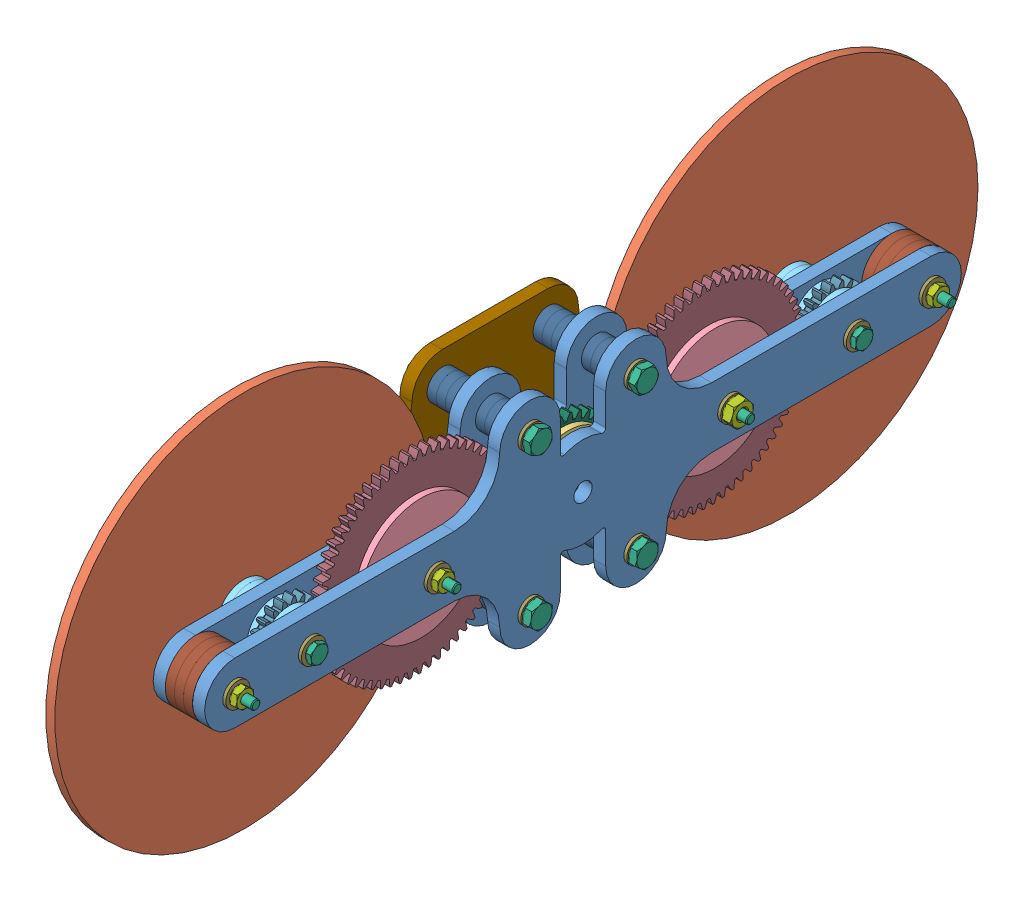
SolidWorks assembly ASSEMBLY LIM Mark 1, configuration Default. Lengths in mm.
Overall size (46 165.05 328.89).
104 component instances, 15 part files, 205 mates.
Components (placement in the parent):
- Frame_4mm-1: Frame_4mm [Default] at (139.7382 18.2666 142.7028) size (4 70 250)
- Wheel-1: Wheel [Default] at (118.7382 18.2666 232.7028) x (1 0 0) z (0 0.063899 0.997956) size (3 125 125)
- Wheel-2: Wheel [Default] at (118.7382 18.2666 52.7028) x (1 0 0) z (0 0.406893 0.913476) size (3 125 125)
- Frame_4mm-2: Frame_4mm [Default] at (126.7382 18.2666 142.7028) size (4 70 250)
- Spacer_driven_2mm-1: Spacer_driven_2mm [Default] at (131.7382 18.2666 142.7028) x (1 0 0) z (0 -0.019023 0.999819) size (2 30 30)
- Spacer_driven_2mm-2: Spacer_driven_2mm [Default] at (136.7382 18.2666 142.7028) x (1 0 0) z (0 0.007581 0.999971) size (2 30 30)
- Spacer_idler_2mm-1: Spacer_idler_2mm [Default] at (136.7382 18.2666 94.2028) x (1 0 0) z (0 0.85666 0.515882) size (2 40 40)
- Spacer_idler_2mm-3: Spacer_idler_2mm [Default] at (136.7382 18.2666 191.2028) x (1 0 0) z (0 0.00445 0.99999) size (2 40 40)
- Spacer_wheel_2mm-1: Spacer_wheel_2mm [Default] at (131.7382 18.2666 232.7028) size (2 18 18)
- Spacer_wheel_2mm-2: Spacer_wheel_2mm [Default] at (136.7382 18.2666 232.7028) x (1 0 0) z (0 0.141629 0.98992) size (2 18 18)
- Spacer_wheel_2mm-4: Spacer_wheel_2mm [Default] at (131.7382 18.2666 52.7028) size (2 18 18)
- hex bolt gradeab_iso-2: hex bolt gradeab_iso [ISO 4014 - M3 x 30 x 12-N] at (146.7382 18.2666 52.7028) x (-1 0 0) z (0 0.901352 0.433087) size (32 6.35 5.5)
- hex bolt gradeab_iso-3: hex bolt gradeab_iso [ISO 4014 - M3 x 30 x 12-N] at (146.7382 18.2666 232.7028) x (-1 0 0) z (0 0.928498 -0.371338) size (32 6.35 5.5)
- hex bolt gradeab_iso-4: hex bolt gradeab_iso [ISO 4014 - M3 x 25 x 12-N] at (123.7382 18.2666 94.2028) x (1 0 0) z (0 0.001655 0.999999) size (27 6.35 5.5)
- hex bolt gradeab_iso-5: hex bolt gradeab_iso [ISO 4014 - M3 x 25 x 12-N] at (123.7382 18.2666 191.2028) x (1 0 0) z (0 -0.941624 0.336667) size (27 6.35 5.5)
- hex bolt gradeab_iso-6: hex bolt gradeab_iso [ISO 4014 - M3 x 25 x 12-N] at (123.7382 18.2666 257.7028) x (1 0 0) z (0 0.542297 0.840187) size (27 6.35 5.5)
- hex bolt gradeab_iso-8: hex bolt gradeab_iso [ISO 4014 - M3 x 25 x 12-N] at (123.7382 18.2666 27.7028) x (1 0 0) z (0 -0.023682 0.99972) size (27 6.35 5.5)
- hex nut style 1 gradeab_iso-3: hex nut style 1 gradeab_iso [ISO - 4032 - M3 - W - N] at (139.1382 18.2666 52.7028) x (0 0.924225 0.381849) z (1 0 0) size (5.5 6.35 2.4)
- hex nut style 1 gradeab_iso-4: hex nut style 1 gradeab_iso [ISO - 4032 - M3 - W - N] at (131.3382 18.2666 52.7028) x (0 0 1) z (-1 0 0) size (5.5 6.35 2.4)
- hex nut style 1 gradeab_iso-5: hex nut style 1 gradeab_iso [ISO - 4032 - M3 - W - N] at (124.1382 18.2666 52.7028) x (0 0.924225 0.381849) z (1 0 0) size (5.5 6.35 2.4)
- hex nut style 1 gradeab_iso-6: hex nut style 1 gradeab_iso [ISO - 4032 - M3 - W - N] at (139.1382 18.2666 232.7028) x (0 -0.924225 -0.381849) z (1 0 0) size (5.5 6.35 2.4)
- hex nut style 1 gradeab_iso-7: hex nut style 1 gradeab_iso [ISO - 4032 - M3 - W - N] at (124.1382 18.2666 232.7028) x (0 0 -1) z (1 0 0) size (5.5 6.35 2.4)
- hex nut style 1 gradeab_iso-11: hex nut style 1 gradeab_iso [ISO - 4032 - M3 - W - N] at (147.1382 18.2666 257.7028) x (0 -0.181908 -0.983316) z (1 0 0) size (5.5 6.35 2.4)
- hex nut style 1 gradeab_iso-13: hex nut style 1 gradeab_iso [ISO - 4032 - M3 - W - N] at (131.3382 18.2666 232.7028) x (0 0 1) z (-1 0 0) size (5.5 6.35 2.4)
- hex nut style 1 gradeab_iso-14: hex nut style 1 gradeab_iso [ISO - 4032 - M3 - W - N] at (116.3382 18.2666 232.7028) x (0 -0.924225 -0.381849) z (-1 0 0) size (5.5 6.35 2.4)
- hex nut style 1 gradeab_iso-15: hex nut style 1 gradeab_iso [ISO - 4032 - M3 - W - N] at (147.1382 18.2666 27.7028) x (0 0.064847 -0.997895) z (1 0 0) size (5.5 6.35 2.4)
- Spacer_idler_circle_2mm-1: Spacer_idler_circle_2mm [Default] at (131.7382 18.2666 191.2028) size (2 40 40)
- Spacer_idler_circle_2mm-2: Spacer_idler_circle_2mm [Default] at (131.7382 18.2666 94.2028) x (1 0 0) z (0 0.14655 0.989203) size (2 40 40)
- Frame_outer_4mm_revised-1: Frame_outer_4mm_revised [Default] at (110.7382 18.2666 142.7028) size (4 70 200)
- hex bolt gradeab_iso-9: hex bolt gradeab_iso [ISO 4014 - M4 x 40 x 14-N] at (147.5382 43.2666 125.2028) x (-1 0 0) z (0 0.591668 0.806182) size (42.8 8.08 7)
- hex bolt gradeab_iso-10: hex bolt gradeab_iso [ISO 4014 - M4 x 40 x 14-N] at (147.5382 -6.7334 125.2028) x (-1 0 0) z (0 -0.935172 -0.354194) size (42.8 8.08 7)
- hex bolt gradeab_iso-11: hex bolt gradeab_iso [ISO 4014 - M4 x 40 x 14-N] at (147.5382 43.2666 160.2028) x (-1 0 0) z (0 -0.143736 0.989616) size (42.8 8.08 7)
- hex bolt gradeab_iso-12: hex bolt gradeab_iso [ISO 4014 - M4 x 40 x 14-N] at (147.5382 -6.7334 160.2028) x (-1 0 0) z (0 -0.737321 0.675543) size (42.8 8.08 7)
- hex nut style 1 gradeab_iso-18: hex nut style 1 gradeab_iso [ISO - 4032 - M4 - W - N] at (106.5382 43.2666 160.2028) x (0 0.358577 0.9335) z (-1 0 0) size (7 8.08 3.2)
- hex nut style 1 gradeab_iso-19: hex nut style 1 gradeab_iso [ISO - 4032 - M4 - W - N] at (106.5382 -6.7334 160.2028) x (0 -0.052351 0.998629) z (-1 0 0) size (7 8.08 3.2)
- hex nut style 1 gradeab_iso-20: hex nut style 1 gradeab_iso [ISO - 4032 - M4 - W - N] at (106.5382 43.2666 125.2028) x (0 0.360849 0.932624) z (-1 0 0) size (7 8.08 3.2)
- hex nut style 1 gradeab_iso-21: hex nut style 1 gradeab_iso [ISO - 4032 - M4 - W - N] at (147.9382 18.2666 94.2028) x (0 -0.986828 -0.161771) z (1 0 0) size (7 8.08 3.2)
- hex nut style 1 gradeab_iso-22: hex nut style 1 gradeab_iso [ISO - 4032 - M3 - W - N] at (116.3382 18.2666 52.7028) x (0 0.924225 0.381849) z (-1 0 0) size (5.5 6.35 2.4)
- hex nut style 1 gradeab_iso-24: hex nut style 1 gradeab_iso [ISO - 4032 - M3 - W - N] at (147.1382 18.2666 191.2028) x (0 0 -1) z (1 0 0) size (5.5 6.35 2.4)
- Spacer_support_inner_3mm-5: Spacer_support_inner_3mm [Default] at (133.7382 43.2666 160.2028) x (-1 0 0) z (0 0.924225 0.381849) size (3 10 10)
- Spacer_support_inner_3mm-6: Spacer_support_inner_3mm [Default] at (139.7382 43.2666 160.2028) x (-1 0 0) z (0 0.924225 0.381849) size (3 10 10)
- Spacer_support_inner_3mm-7: Spacer_support_inner_3mm [Default] at (136.7382 43.2666 125.2028) x (-1 0 0) z (0 0.924225 0.381849) size (3 10 10)
- Spacer_support_inner_3mm-8: Spacer_support_inner_3mm [Default] at (133.7382 43.2666 125.2028) x (-1 0 0) z (0 0.924225 0.381849) size (3 10 10)
- Spacer_support_inner_3mm-9: Spacer_support_inner_3mm [Default] at (139.7382 -6.7334 125.2028) x (-1 0 0) z (0 0.924225 0.381849) size (3 10 10)
- Spacer_support_inner_3mm-10: Spacer_support_inner_3mm [Default] at (136.7382 43.2666 160.2028) x (-1 0 0) z (0 0.924225 0.381849) size (3 10 10)
- Spacer_support_inner_3mm-11: Spacer_support_inner_3mm [Default] at (136.7382 43.2666 125.2028) size (3 10 10)
- Spacer_support_outer_3mm-8: Spacer_support_outer_3mm [Default] at (133.7382 18.2666 27.7028) size (3 20 20)
- Spacer_support_outer_3mm-9: Spacer_support_outer_3mm [Default] at (136.7382 18.2666 27.7028) size (3 20 20)
- Spacer_support_outer_3mm-10: Spacer_support_outer_3mm [Default] at (130.7382 18.2666 27.7028) size (3 20 20)
- Spacer_support_outer_3mm-12: Spacer_support_outer_3mm [Default] at (139.7382 18.2666 257.7028) x (-1 0 0) z (0 0.924225 0.381849) size (3 20 20)
- Spacer_support_outer_3mm-13: Spacer_support_outer_3mm [Default] at (130.7382 18.2666 257.7028) size (3 20 20)
- Spacer_support_outer_3mm-16: Spacer_support_outer_3mm [Default] at (133.7382 18.2666 257.7028) size (3 20 20)
- plain washer 10669 type nl_iso-1: plain washer 10669 type nl_iso [ISO 10669-3-N] at (143.7382 43.2666 125.2028) size (1 8 8)
- plain washer 10669 type nl_iso-2: plain washer 10669 type nl_iso [ISO 10669-3-N] at (144.7382 18.2666 257.7028) x (-1 0 0) z (0 0.924225 0.381849) size (1 8 8)
- plain washer 10669 type nl_iso-3: plain washer 10669 type nl_iso [ISO 10669-3-N] at (144.7382 18.2666 232.7028) x (-1 0 0) z (0 0.924225 0.381849) size (1 8 8)
- plain washer 10669 type nl_iso-4: plain washer 10669 type nl_iso [ISO 10669-3-N] at (144.7382 18.2666 191.2028) x (-1 0 0) z (0 0.924225 0.381849) size (1 8 8)
- plain washer 10669 type nl_iso-5: plain washer 10669 type nl_iso [ISO 10669-3-N] at (144.7382 18.2666 94.2028) x (-1 0 0) z (0 0.939531 0.342464) size (1 8 8)
- plain washer 10669 type nl_iso-6: plain washer 10669 type nl_iso [ISO 10669-3-N] at (126.7382 18.2666 191.2028) x (-1 0 0) z (0 0.355388 0.934719) size (1 8 8)
- plain washer 10669 type nl_iso-7: plain washer 10669 type nl_iso [ISO 10669-3-N] at (125.7382 18.2666 257.7028) size (1 8 8)
- plain washer 10669 type nl_iso-8: plain washer 10669 type nl_iso [ISO 10669-3-N] at (125.7382 18.2666 27.7028) x (1 0 0) z (0 -0.53185 0.846839) size (1 8 8)
- plain washer 10669 type nl_iso-10: plain washer 10669 type nl_iso [ISO 10669-3-N] at (110.7382 -6.7334 160.2028) x (-1 0 0) z (0 -0.924225 -0.381849) size (1 8 8)
- plain washer 10669 type nl_iso-11: plain washer 10669 type nl_iso [ISO 10669-3-N] at (110.7382 43.2666 125.2028) x (-1 0 0) z (0 0.924225 0.381849) size (1 8 8)
- plain washer 10669 type nl_iso-12: plain washer 10669 type nl_iso [ISO 10669-3-N] at (110.7382 43.2666 160.2028) x (-1 0 0) z (0 0.924225 0.381849) size (1 8 8)
- plain washer 10669 type nl_iso-13: plain washer 10669 type nl_iso [ISO 10669-3-N] at (110.7382 -6.7334 125.2028) x (-1 0 0) z (0 0.924225 0.381849) size (1 8 8)
- plain washer 10669 type nl_iso-15: plain washer 10669 type nl_iso [ISO 10669-3-N] at (144.7382 43.2666 160.2028) x (-1 0 0) z (0 0.924225 0.381849) size (1 8 8)
- plain washer 10669 type nl_iso-16: plain washer 10669 type nl_iso [ISO 10669-3-N] at (144.7382 18.2666 27.7028) x (-1 0 0) z (0 0.924225 0.381849) size (1 8 8)
- plain washer 10669 type nl_iso-17: plain washer 10669 type nl_iso [ISO 10669-3-N] at (126.7382 18.2666 94.2028) x (-1 0 0) z (0 -0.924225 -0.381849) size (1 8 8)
- plain washer 10669 type nl_iso-18: plain washer 10669 type nl_iso [ISO 10669-3-N] at (143.7382 -6.7334 125.2028) size (1 8 8)
- plain washer 10669 type nl_iso-19: plain washer 10669 type nl_iso [ISO 10669-3-N] at (144.7382 -6.7334 160.2028) x (-1 0 0) z (0 0.924225 0.381849) size (1 8 8)
- plain washer 10669 type nl_iso-20: plain washer 10669 type nl_iso [ISO 10669-3-N] at (144.7382 18.2666 52.7028) x (-1 0 0) z (0 0.924225 0.381849) size (1 8 8)
- Spacer_support_inner_3mm-14: Spacer_support_inner_3mm [Default] at (133.7382 -6.7334 160.2028) size (3 10 10)
- Spacer_support_inner_3mm-17: Spacer_support_inner_3mm [Default] at (130.7382 -6.7334 160.2028) size (3 10 10)
- Spacer_support_inner_3mm-18: Spacer_support_inner_3mm [Default] at (136.7382 -6.7334 160.2028) size (3 10 10)
- Spacer_support_inner_3mm-19: Spacer_support_inner_3mm [Default] at (130.7382 -6.7334 125.2028) size (3 10 10)
- Spacer_support_inner_3mm-20: Spacer_support_inner_3mm [Default] at (133.7382 -6.7334 125.2028) size (3 10 10)
- Spacer_support_inner_3mm-21: Spacer_support_inner_3mm [Default] at (117.7382 43.2666 125.2028) size (3 10 10)
- Spacer_support_inner_3mm-22: Spacer_support_inner_3mm [Default] at (126.7382 43.2666 125.2028) x (-1 0 0) z (0 0.924225 0.381849) size (3 10 10)
- Spacer_support_inner_3mm-23: Spacer_support_inner_3mm [Default] at (120.7382 43.2666 125.2028) size (3 10 10)
- Spacer_support_inner_3mm-24: Spacer_support_inner_3mm [Default] at (120.7382 -6.7334 160.2028) size (3 10 10)
- Spacer_support_inner_3mm-25: Spacer_support_inner_3mm [Default] at (126.7382 -6.7334 160.2028) x (-1 0 0) z (0 0.924225 0.381849) size (3 10 10)
- Spacer_support_inner_3mm-26: Spacer_support_inner_3mm [Default] at (117.7382 -6.7334 160.2028) size (3 10 10)
- Spacer_support_inner_3mm-27: Spacer_support_inner_3mm [Default] at (120.7382 43.2666 160.2028) size (3 10 10)
- Spacer_support_inner_3mm-28: Spacer_support_inner_3mm [Default] at (126.7382 43.2666 160.2028) x (-1 0 0) z (0 0.924225 0.381849) size (3 10 10)
- Spacer_support_inner_3mm-29: Spacer_support_inner_3mm [Default] at (117.7382 43.2666 160.2028) size (3 10 10)
- Spacer_support_inner_3mm-30: Spacer_support_inner_3mm [Default] at (120.7382 -6.7334 125.2028) size (3 10 10)
- Spacer_support_inner_3mm-31: Spacer_support_inner_3mm [Default] at (126.7382 -6.7334 125.2028) x (-1 0 0) z (0 0.924225 0.381849) size (3 10 10)
- Spacer_support_inner_3mm-32: Spacer_support_inner_3mm [Default] at (117.7382 -6.7334 125.2028) size (3 10 10)
- Spacer_wheel_2mm-10: Spacer_wheel_2mm [Default] at (123.7382 18.2666 52.7028) x (1 0 0) z (0 -0.924225 -0.381849) size (2 18 18)
- Spacer_wheel_2mm-11: Spacer_wheel_2mm [Default] at (123.7382 18.2666 52.7028) x (-1 0 0) z (0 -0.131421 -0.991327) size (2 18 18)
- Spacer_wheel_2mm-14: Spacer_wheel_2mm [Default] at (123.7382 18.2666 232.7028) x (-1 0 0) z (0 -0.866025 0.5) size (2 18 18)
- Spacer_wheel_2mm-15: Spacer_wheel_2mm [Default] at (123.7382 18.2666 232.7028) size (2 18 18)
- Spacer_support_inner_3mm-33: Spacer_support_inner_3mm [Default] at (117.7382 43.2666 125.2028) x (-1 0 0) z (0 0.924225 0.381849) size (3 10 10)
- Spacer_support_inner_3mm-34: Spacer_support_inner_3mm [Default] at (117.7382 -6.7334 125.2028) x (-1 0 0) z (0 0.924225 0.381849) size (3 10 10)
- Spacer_support_inner_3mm-35: Spacer_support_inner_3mm [Default] at (117.7382 -6.7334 160.2028) x (-1 0 0) z (0 0.924225 0.381849) size (3 10 10)
- Spacer_support_inner_3mm-36: Spacer_support_inner_3mm [Default] at (117.7382 43.2666 160.2028) x (-1 0 0) z (0 0.924225 0.381849) size (3 10 10)
- Spacer_support_outer_3mm-20: Spacer_support_outer_3mm [Default] at (115.7382 18.2666 52.7028) size (3 20 20)
- Spacer_support_outer_3mm-21: Spacer_support_outer_3mm [Default] at (115.7382 18.2666 232.7028) size (3 20 20)
- hex nut style 1 gradeab_iso-25: hex nut style 1 gradeab_iso [ISO - 4032 - M4 - W - N] at (106.5382 -6.7334 125.2028) x (0 -0.052351 0.998629) z (-1 0 0) size (7 8.08 3.2)
- Spacer_wheel_2mm-16: Spacer_wheel_2mm [Default] at (136.7382 18.2666 52.7028) x (1 0 0) z (0 0.141629 0.98992) size (2 18 18)
- Gear_idler_3mm-3: Gear_idler_3mm [ISO - Spur gear 1M 62T 20PA 3FW ---S62A75H50L3.0N] at (133.7382 18.2666 191.2028) size (3 63.95 64)
- Gear_idler_3mm-4: Gear_idler_3mm [ISO - Spur gear 1M 62T 20PA 3FW ---S62A75H50L3.0N] at (133.7382 18.2666 94.2028) size (3 63.95 64)
- Gear_slave_3mm-3: Gear_slave_3mm [ISO - Spur gear 1M 20T 20PA 3FW ---S20A75H50L3.0N] at (133.7382 18.2666 232.7028) size (3 21.8 21.8)
- Gear_slave_3mm-4: Gear_slave_3mm [ISO - Spur gear 1M 20T 20PA 3FW ---S20A75H50L3.0N] at (133.7382 18.2666 52.7028) x (1 0 0) z (0 0.10181 0.994804) size (3 21.8 21.8)
- Gear_master_3mm-2: Gear_master_3mm [ISO - Spur gear 1M 34T 20PA 3FW ---S34A75H50L3.0N] at (133.7382 18.2666 142.7028) x (1 0 0) z (0 -0.290928 0.956745) size (3 35.9 36)
Mates (geometry in assembly coordinates):
- Distance1: distance = 1 mm anti-aligned: plane of Frame_4mm-1 through (139.7382 18.2666 142.7028) normal (-1 0 0); plane of Spacer_driven_2mm-2 through (138.7382 18.2666 142.7028) normal (1 0 0)
- Coincident326: coincident aligned: axis of Frame_4mm-1 through (139.7382 43.2666 125.2028) axis (1 0 0); axis of hex bolt gradeab_iso-9 through (105.1282 43.2666 125.2028) axis (1 0 0)
- Coincident330: coincident anti-aligned: axis of hex bolt gradeab_iso-9 through (105.1282 43.2666 125.2028) axis (1 0 0); axis of plain washer 10669 type nl_iso-1 through (144.7382 43.2666 125.2028) axis (-1 0 0)
- Coincident331: coincident anti-aligned: plane of hex bolt gradeab_iso-9 through (144.7382 40.0085 127.594) normal (-1 0 0); plane of plain washer 10669 type nl_iso-1 through (144.7382 43.2666 125.2028) normal (1 0 0)
- Coincident332: coincident anti-aligned: plane of Frame_4mm-1 through (143.7382 18.2666 142.7028) normal (1 0 0); plane of plain washer 10669 type nl_iso-1 through (143.7382 43.2666 125.2028) normal (-1 0 0)
- Coincident335: coincident aligned: axis of Frame_4mm-1 through (139.7382 18.2666 257.7028) axis (1 0 0); axis of plain washer 10669 type nl_iso-2 through (143.7382 18.2666 257.7028) axis (1 0 0)
- Coincident336: coincident anti-aligned: plane of Frame_4mm-1 through (143.7382 18.2666 142.7028) normal (1 0 0); plane of plain washer 10669 type nl_iso-2 through (143.7382 18.2666 257.7028) normal (-1 0 0)
- Coincident337: coincident anti-aligned: axis of Frame_4mm-1 through (139.7382 -6.7334 125.2028) axis (1 0 0); axis of plain washer 10669 type nl_iso-18 through (144.7382 -6.7334 125.2028) axis (-1 0 0)
- Coincident338: coincident anti-aligned: plane of Frame_4mm-1 through (143.7382 18.2666 142.7028) normal (1 0 0); plane of plain washer 10669 type nl_iso-18 through (143.7382 -6.7334 125.2028) normal (-1 0 0)
- Coincident339: coincident aligned: axis of Frame_4mm-1 through (139.7382 -6.7334 160.2028) axis (1 0 0); axis of plain washer 10669 type nl_iso-19 through (143.7382 -6.7334 160.2028) axis (1 0 0)
- Coincident340: coincident anti-aligned: plane of Frame_4mm-1 through (143.7382 18.2666 142.7028) normal (1 0 0); plane of plain washer 10669 type nl_iso-19 through (143.7382 -6.7334 160.2028) normal (-1 0 0)
- Coincident341: coincident aligned: axis of Frame_4mm-1 through (139.7382 43.2666 160.2028) axis (1 0 0); axis of plain washer 10669 type nl_iso-15 through (143.7382 43.2666 160.2028) axis (1 0 0)
- Coincident342: coincident anti-aligned: plane of Frame_4mm-1 through (143.7382 18.2666 142.7028) normal (1 0 0); plane of plain washer 10669 type nl_iso-15 through (143.7382 43.2666 160.2028) normal (-1 0 0)
- Coincident343: coincident aligned: axis of Frame_4mm-1 through (139.7382 18.2666 232.7028) axis (1 0 0); axis of plain washer 10669 type nl_iso-3 through (143.7382 18.2666 232.7028) axis (1 0 0)
- Coincident344: coincident anti-aligned: plane of Frame_4mm-1 through (143.7382 18.2666 142.7028) normal (1 0 0); plane of plain washer 10669 type nl_iso-3 through (143.7382 18.2666 232.7028) normal (-1 0 0)
- Coincident347: coincident aligned: axis of Frame_4mm-1 through (139.7382 18.2666 191.2028) axis (1 0 0); axis of plain washer 10669 type nl_iso-4 through (143.7382 18.2666 191.2028) axis (1 0 0)
- Coincident348: coincident anti-aligned: plane of Frame_4mm-1 through (143.7382 18.2666 142.7028) normal (1 0 0); plane of plain washer 10669 type nl_iso-4 through (143.7382 18.2666 191.2028) normal (-1 0 0)
- Coincident349: coincident aligned: axis of Frame_4mm-1 through (139.7382 18.2666 94.2028) axis (1 0 0); axis of plain washer 10669 type nl_iso-5 through (143.7382 18.2666 94.2028) axis (1 0 0)
- Coincident350: coincident anti-aligned: plane of Frame_4mm-1 through (143.7382 18.2666 142.7028) normal (1 0 0); plane of plain washer 10669 type nl_iso-5 through (143.7382 18.2666 94.2028) normal (-1 0 0)
- Coincident351: coincident aligned: axis of Frame_4mm-1 through (139.7382 18.2666 52.7028) axis (1 0 0); axis of plain washer 10669 type nl_iso-20 through (143.7382 18.2666 52.7028) axis (1 0 0)
- Coincident352: coincident anti-aligned: plane of Frame_4mm-1 through (143.7382 18.2666 142.7028) normal (1 0 0); plane of plain washer 10669 type nl_iso-20 through (143.7382 18.2666 52.7028) normal (-1 0 0)
- Coincident353: coincident aligned: axis of Frame_4mm-1 through (139.7382 18.2666 27.7028) axis (1 0 0); axis of plain washer 10669 type nl_iso-16 through (143.7382 18.2666 27.7028) axis (1 0 0)
- Coincident354: coincident anti-aligned: plane of Frame_4mm-1 through (143.7382 18.2666 142.7028) normal (1 0 0); plane of plain washer 10669 type nl_iso-16 through (143.7382 18.2666 27.7028) normal (-1 0 0)
- Coincident355: coincident aligned: axis of hex bolt gradeab_iso-2 through (115.0187 18.2666 52.7028) axis (1 0 0); axis of plain washer 10669 type nl_iso-20 through (143.7382 18.2666 52.7028) axis (1 0 0)
- Coincident356: coincident anti-aligned: plane of hex bolt gradeab_iso-2 through (144.7382 16.8914 55.5649) normal (-1 0 0); plane of plain washer 10669 type nl_iso-20 through (144.7382 18.2666 52.7028) normal (1 0 0)
- Concentric3: concentric aligned: axis of hex bolt gradeab_iso-10 through (146.799 -6.7334 125.2028) axis (1 0 0); circle of plain washer 10669 type nl_iso-18
- Coincident357: coincident aligned: axis of Frame_4mm-1 through (139.7382 43.2666 160.2028) axis (1 0 0); axis of hex bolt gradeab_iso-11 through (105.1282 43.2666 160.2028) axis (1 0 0)
- Coincident358: coincident anti-aligned: plane of hex bolt gradeab_iso-11 through (144.7382 39.2671 159.6219) normal (-1 0 0); plane of plain washer 10669 type nl_iso-15 through (144.7382 43.2666 160.2028) normal (1 0 0)
- Coincident359: coincident anti-aligned: plane of hex bolt gradeab_iso-10 through (144.7382 -5.3019 121.4233) normal (-1 0 0); plane of plain washer 10669 type nl_iso-18 through (144.7382 -6.7334 125.2028) normal (1 0 0)
- Coincident360: coincident aligned: axis of hex bolt gradeab_iso-12 through (105.1282 -6.7334 160.2028) axis (1 0 0); axis of plain washer 10669 type nl_iso-19 through (143.7382 -6.7334 160.2028) axis (1 0 0)
- Coincident361: coincident anti-aligned: plane of hex bolt gradeab_iso-12 through (144.7382 -9.4636 157.2229) normal (-1 0 0); plane of plain washer 10669 type nl_iso-19 through (144.7382 -6.7334 160.2028) normal (1 0 0)
- Coincident362: coincident aligned: axis of Frame_4mm-1 through (139.7382 18.2666 232.7028) axis (1 0 0); axis of hex bolt gradeab_iso-3 through (146.1574 18.2666 232.7028) axis (1 0 0)
- Coincident363: coincident anti-aligned: plane of hex bolt gradeab_iso-3 through (144.7382 19.4458 235.6511) normal (-1 0 0); plane of plain washer 10669 type nl_iso-3 through (144.7382 18.2666 232.7028) normal (1 0 0)
- Coincident364: coincident aligned: axis of hex bolt gradeab_iso-11 through (105.1282 43.2666 160.2028) axis (1 0 0); axis of Spacer_support_inner_3mm-6 through (136.7382 43.2666 160.2028) axis (1 0 0)
- Coincident365: coincident anti-aligned: plane of Frame_4mm-1 through (139.7382 18.2666 142.7028) normal (-1 0 0); plane of Spacer_support_inner_3mm-6 through (139.7382 43.2666 160.2028) normal (1 0 0)
- Coincident366: coincident aligned: axis of hex bolt gradeab_iso-11 through (105.1282 43.2666 160.2028) axis (1 0 0); axis of Spacer_support_inner_3mm-10 through (133.7382 43.2666 160.2028) axis (1 0 0)
- Coincident367: coincident anti-aligned: plane of Spacer_support_inner_3mm-6 through (136.7382 43.2666 160.2028) normal (-1 0 0); plane of Spacer_support_inner_3mm-10 through (136.7382 43.2666 160.2028) normal (1 0 0)
- Coincident368: coincident aligned: axis of hex bolt gradeab_iso-11 through (105.1282 43.2666 160.2028) axis (1 0 0); axis of Spacer_support_inner_3mm-5 through (130.7382 43.2666 160.2028) axis (1 0 0)
- Coincident369: coincident anti-aligned: plane of Spacer_support_inner_3mm-5 through (133.7382 43.2666 160.2028) normal (1 0 0); plane of Spacer_support_inner_3mm-10 through (133.7382 43.2666 160.2028) normal (-1 0 0)
- Coincident370: coincident aligned: axis of hex bolt gradeab_iso-9 through (105.1282 43.2666 125.2028) axis (1 0 0); axis of Spacer_support_inner_3mm-7 through (133.7382 43.2666 125.2028) axis (1 0 0)
- Coincident371: coincident anti-aligned: axis of hex bolt gradeab_iso-9 through (105.1282 43.2666 125.2028) axis (1 0 0); axis of Spacer_support_inner_3mm-11 through (139.7382 43.2666 125.2028) axis (-1 0 0)
- Coincident372: coincident anti-aligned: plane of Frame_4mm-1 through (139.7382 18.2666 142.7028) normal (-1 0 0); plane of Spacer_support_inner_3mm-11 through (139.7382 43.2666 125.2028) normal (1 0 0)
- Coincident373: coincident anti-aligned: plane of Spacer_support_inner_3mm-7 through (136.7382 43.2666 125.2028) normal (1 0 0); plane of Spacer_support_inner_3mm-11 through (136.7382 43.2666 125.2028) normal (-1 0 0)
- Coincident374: coincident aligned: axis of hex bolt gradeab_iso-9 through (105.1282 43.2666 125.2028) axis (1 0 0); axis of Spacer_support_inner_3mm-8 through (130.7382 43.2666 125.2028) axis (1 0 0)
- Coincident375: coincident anti-aligned: plane of Spacer_support_inner_3mm-7 through (133.7382 43.2666 125.2028) normal (-1 0 0); plane of Spacer_support_inner_3mm-8 through (133.7382 43.2666 125.2028) normal (1 0 0)
- Coincident376: coincident aligned: axis of hex nut style 1 gradeab_iso-15 through (144.9387 18.2666 27.7028) axis (1 0 0); axis of plain washer 10669 type nl_iso-16 through (143.7382 18.2666 27.7028) axis (1 0 0)
- Coincident377: coincident anti-aligned: plane of hex nut style 1 gradeab_iso-15 through (144.7382 21.4353 27.9087) normal (-1 0 0); plane of plain washer 10669 type nl_iso-16 through (144.7382 18.2666 27.7028) normal (1 0 0)
- Coincident380: coincident aligned: axis of hex nut style 1 gradeab_iso-21 through (145.0087 18.2666 94.2028) axis (1 0 0); axis of plain washer 10669 type nl_iso-5 through (143.7382 18.2666 94.2028) axis (1 0 0)
- Coincident381: coincident aligned: axis of hex nut style 1 gradeab_iso-24 through (144.9387 18.2666 191.2028) axis (1 0 0); axis of plain washer 10669 type nl_iso-4 through (143.7382 18.2666 191.2028) axis (1 0 0)
- Coincident382: coincident anti-aligned: plane of hex nut style 1 gradeab_iso-24 through (144.7382 21.442 191.2028) normal (-1 0 0); plane of plain washer 10669 type nl_iso-4 through (144.7382 18.2666 191.2028) normal (1 0 0)
- Coincident383: coincident aligned: axis of hex nut style 1 gradeab_iso-11 through (144.9387 18.2666 257.7028) axis (1 0 0); axis of plain washer 10669 type nl_iso-2 through (143.7382 18.2666 257.7028) axis (1 0 0)
- Coincident384: coincident anti-aligned: plane of hex nut style 1 gradeab_iso-11 through (144.7382 21.389 257.1251) normal (-1 0 0); plane of plain washer 10669 type nl_iso-2 through (144.7382 18.2666 257.7028) normal (1 0 0)
- Coincident385: coincident anti-aligned: plane of Frame_4mm-1 through (139.7382 18.2666 142.7028) normal (-1 0 0); plane of Spacer_support_outer_3mm-12 through (139.7382 18.2666 257.7028) normal (1 0 0)
- Coincident386: coincident aligned: axis of Frame_4mm-1 through (139.7382 18.2666 257.7028) axis (1 0 0); axis of Spacer_support_outer_3mm-12 through (136.7382 18.2666 257.7028) axis (1 0 0)
- Coincident387: coincident anti-aligned: plane of Spacer_support_outer_3mm-12 through (136.7382 18.2666 257.7028) normal (-1 0 0); plane of Spacer_support_outer_3mm-16 through (136.7382 18.2666 257.7028) normal (1 0 0)
- Coincident388: coincident anti-aligned: axis of Spacer_support_outer_3mm-12 through (136.7382 18.2666 257.7028) axis (1 0 0); axis of Spacer_support_outer_3mm-16 through (136.7382 18.2666 257.7028) axis (-1 0 0)
- Coincident390: coincident anti-aligned: plane of Spacer_support_outer_3mm-13 through (133.7382 18.2666 257.7028) normal (1 0 0); plane of Spacer_support_outer_3mm-16 through (133.7382 18.2666 257.7028) normal (-1 0 0)
- Coincident391: coincident aligned: axis of Spacer_support_outer_3mm-13 through (133.7382 18.2666 257.7028) axis (-1 0 0); axis of Spacer_support_outer_3mm-16 through (136.7382 18.2666 257.7028) axis (-1 0 0)
- Distance2: distance = 1 mm anti-aligned: plane of Spacer_idler_2mm-3 through (138.7382 18.2666 191.2028) normal (1 0 0); plane of Frame_4mm-1 through (139.7382 18.2666 142.7028) normal (-1 0 0)
- Coincident393: coincident anti-aligned: axis of Spacer_idler_2mm-3 through (138.7382 18.2666 191.2028) axis (-1 0 0); axis of hex nut style 1 gradeab_iso-24 through (144.9387 18.2666 191.2028) axis (1 0 0)
- Distance3: distance = 1 mm anti-aligned: plane of Frame_4mm-1 through (139.7382 18.2666 142.7028) normal (-1 0 0); plane of Spacer_wheel_2mm-2 through (138.7382 18.2666 232.7028) normal (1 0 0)
- Coincident395: coincident anti-aligned: axis of Spacer_wheel_2mm-2 through (138.7382 18.2666 232.7028) axis (-1 0 0); axis of hex bolt gradeab_iso-3 through (115.0187 18.2666 232.7028) axis (1 0 0)
- Coincident396: coincident aligned: axis of hex bolt gradeab_iso-10 through (105.1282 -6.7334 125.2028) axis (1 0 0); axis of Spacer_support_inner_3mm-9 through (136.7382 -6.7334 125.2028) axis (1 0 0)
- Coincident397: coincident anti-aligned: plane of Frame_4mm-1 through (139.7382 18.2666 142.7028) normal (-1 0 0); plane of Spacer_support_inner_3mm-9 through (139.7382 -6.7334 125.2028) normal (1 0 0)
- Coincident398: coincident anti-aligned: axis of hex bolt gradeab_iso-10 through (105.1282 -6.7334 125.2028) axis (1 0 0); axis of Spacer_support_inner_3mm-20 through (136.7382 -6.7334 125.2028) axis (-1 0 0)
- Coincident399: coincident anti-aligned: plane of Spacer_support_inner_3mm-9 through (136.7382 -6.7334 125.2028) normal (-1 0 0); plane of Spacer_support_inner_3mm-20 through (136.7382 -6.7334 125.2028) normal (1 0 0)
- Coincident400: coincident anti-aligned: plane of Spacer_support_inner_3mm-19 through (133.7382 -6.7334 125.2028) normal (1 0 0); plane of Spacer_support_inner_3mm-20 through (133.7382 -6.7334 125.2028) normal (-1 0 0)
- Coincident401: coincident anti-aligned: axis of hex bolt gradeab_iso-10 through (105.1282 -6.7334 125.2028) axis (1 0 0); axis of Spacer_support_inner_3mm-19 through (133.7382 -6.7334 125.2028) axis (-1 0 0)
- Coincident402: coincident anti-aligned: axis of hex bolt gradeab_iso-12 through (105.1282 -6.7334 160.2028) axis (1 0 0); axis of Spacer_support_inner_3mm-18 through (139.7382 -6.7334 160.2028) axis (-1 0 0)
- Coincident403: coincident anti-aligned: plane of Frame_4mm-1 through (139.7382 18.2666 142.7028) normal (-1 0 0); plane of Spacer_support_inner_3mm-18 through (139.7382 -6.7334 160.2028) normal (1 0 0)
- Coincident404: coincident anti-aligned: axis of hex bolt gradeab_iso-12 through (105.1282 -6.7334 160.2028) axis (1 0 0); axis of Spacer_support_inner_3mm-17 through (133.7382 -6.7334 160.2028) axis (-1 0 0)
- Coincident405: coincident anti-aligned: axis of hex bolt gradeab_iso-12 through (105.1282 -6.7334 160.2028) axis (1 0 0); axis of Spacer_support_inner_3mm-14 through (136.7382 -6.7334 160.2028) axis (-1 0 0)
- Coincident406: coincident anti-aligned: plane of Spacer_support_inner_3mm-14 through (136.7382 -6.7334 160.2028) normal (1 0 0); plane of Spacer_support_inner_3mm-18 through (136.7382 -6.7334 160.2028) normal (-1 0 0)
- Coincident407: coincident anti-aligned: plane of Spacer_support_inner_3mm-14 through (133.7382 -6.7334 160.2028) normal (-1 0 0); plane of Spacer_support_inner_3mm-17 through (133.7382 -6.7334 160.2028) normal (1 0 0)
- Distance4: distance = 1 mm anti-aligned: plane of Spacer_idler_2mm-1 through (138.7382 18.2666 94.2028) normal (1 0 0); plane of Frame_4mm-1 through (139.7382 18.2666 142.7028) normal (-1 0 0)
- Coincident411: coincident anti-aligned: axis of Spacer_idler_2mm-1 through (138.7382 18.2666 94.2028) axis (-1 0 0); axis of hex nut style 1 gradeab_iso-21 through (145.0087 18.2666 94.2028) axis (1 0 0)
- Coincident414: coincident anti-aligned: axis of Frame_4mm-1 through (139.7382 18.2666 27.7028) axis (1 0 0); axis of Spacer_support_outer_3mm-10 through (133.7382 18.2666 27.7028) axis (-1 0 0)
- Coincident415: coincident aligned: axis of Spacer_support_outer_3mm-9 through (139.7382 18.2666 27.7028) axis (-1 0 0); axis of Spacer_support_outer_3mm-10 through (133.7382 18.2666 27.7028) axis (-1 0 0)
- Coincident416: coincident aligned: axis of Spacer_support_outer_3mm-8 through (136.7382 18.2666 27.7028) axis (-1 0 0); axis of Spacer_support_outer_3mm-10 through (133.7382 18.2666 27.7028) axis (-1 0 0)
- Coincident417: coincident anti-aligned: plane of Spacer_support_outer_3mm-8 through (133.7382 18.2666 27.7028) normal (-1 0 0); plane of Spacer_support_outer_3mm-10 through (133.7382 18.2666 27.7028) normal (1 0 0)
- Coincident418: coincident anti-aligned: plane of Spacer_support_outer_3mm-8 through (136.7382 18.2666 27.7028) normal (1 0 0); plane of Spacer_support_outer_3mm-9 through (136.7382 18.2666 27.7028) normal (-1 0 0)
- Coincident419: coincident anti-aligned: plane of Frame_4mm-1 through (139.7382 18.2666 142.7028) normal (-1 0 0); plane of Spacer_support_outer_3mm-9 through (139.7382 18.2666 27.7028) normal (1 0 0)
- Coincident422: coincident aligned: axis of Frame_outer_4mm_revised-1 through (110.7382 -6.7334 125.2028) axis (1 0 0); axis of plain washer 10669 type nl_iso-13 through (109.7382 -6.7334 125.2028) axis (1 0 0)
- Coincident423: coincident anti-aligned: plane of Frame_outer_4mm_revised-1 through (110.7382 18.2666 142.7028) normal (-1 0 0); plane of plain washer 10669 type nl_iso-13 through (110.7382 -6.7334 125.2028) normal (1 0 0)
- Coincident424: coincident aligned: axis of Frame_outer_4mm_revised-1 through (110.7382 43.2666 125.2028) axis (1 0 0); axis of plain washer 10669 type nl_iso-11 through (109.7382 43.2666 125.2028) axis (1 0 0)
- Coincident425: coincident anti-aligned: plane of Frame_outer_4mm_revised-1 through (110.7382 18.2666 142.7028) normal (-1 0 0); plane of plain washer 10669 type nl_iso-11 through (110.7382 43.2666 125.2028) normal (1 0 0)
- Coincident426: coincident aligned: axis of Frame_outer_4mm_revised-1 through (110.7382 43.2666 160.2028) axis (1 0 0); axis of plain washer 10669 type nl_iso-12 through (109.7382 43.2666 160.2028) axis (1 0 0)
- Coincident427: coincident anti-aligned: plane of Frame_outer_4mm_revised-1 through (110.7382 18.2666 142.7028) normal (-1 0 0); plane of plain washer 10669 type nl_iso-12 through (110.7382 43.2666 160.2028) normal (1 0 0)
- Coincident428: coincident anti-aligned: plane of Frame_outer_4mm_revised-1 through (110.7382 18.2666 142.7028) normal (-1 0 0); plane of plain washer 10669 type nl_iso-10 through (110.7382 -6.7334 160.2028) normal (1 0 0)
- Coincident429: coincident aligned: axis of Frame_outer_4mm_revised-1 through (110.7382 -6.7334 160.2028) axis (1 0 0); axis of plain washer 10669 type nl_iso-10 through (109.7382 -6.7334 160.2028) axis (1 0 0)
- Coincident435: coincident anti-aligned: axis of Frame_outer_4mm_revised-1 through (110.7382 43.2666 160.2028) axis (1 0 0); axis of hex nut style 1 gradeab_iso-18 through (109.4678 43.2666 160.2028) axis (-1 0 0)
- Coincident436: coincident anti-aligned: plane of hex nut style 1 gradeab_iso-18 through (109.7382 47.0393 158.7536) normal (1 0 0); plane of plain washer 10669 type nl_iso-12 through (109.7382 43.2666 160.2028) normal (-1 0 0)
- Coincident437: coincident anti-aligned: axis of Frame_outer_4mm_revised-1 through (110.7382 43.2666 125.2028) axis (1 0 0); axis of hex nut style 1 gradeab_iso-20 through (109.4678 43.2666 125.2028) axis (-1 0 0)
- Coincident438: coincident anti-aligned: plane of hex nut style 1 gradeab_iso-20 through (109.7382 47.0358 123.7444) normal (1 0 0); plane of plain washer 10669 type nl_iso-11 through (109.7382 43.2666 125.2028) normal (-1 0 0)
- Coincident441: coincident anti-aligned: axis of Frame_outer_4mm_revised-1 through (110.7382 -6.7334 160.2028) axis (1 0 0); axis of hex nut style 1 gradeab_iso-19 through (109.4678 -6.7334 160.2028) axis (-1 0 0)
- Coincident442: coincident anti-aligned: plane of hex nut style 1 gradeab_iso-19 through (109.7382 -2.6975 160.4143) normal (1 0 0); plane of plain washer 10669 type nl_iso-10 through (109.7382 -6.7334 160.2028) normal (-1 0 0)
- Coincident467: coincident aligned: axis of hex bolt gradeab_iso-2 through (115.0187 18.2666 52.7028) axis (1 0 0); axis of hex nut style 1 gradeab_iso-3 through (136.9387 18.2666 52.7028) axis (1 0 0)
- Coincident474: coincident anti-aligned: axis of Spacer_wheel_2mm-4 through (133.7382 18.2666 52.7028) axis (-1 0 0); axis of hex bolt gradeab_iso-2 through (115.0187 18.2666 52.7028) axis (1 0 0)
- Coincident475: coincident anti-aligned: axis of hex bolt gradeab_iso-2 through (115.0187 18.2666 52.7028) axis (1 0 0); axis of hex nut style 1 gradeab_iso-4 through (133.5378 18.2666 52.7028) axis (-1 0 0)
- Coincident479: coincident aligned: axis of Spacer_idler_2mm-1 through (138.7382 18.2666 94.2028) axis (-1 0 0); axis of hex bolt gradeab_iso-4 through (150.4577 18.2666 94.2028) axis (-1 0 0)
- Coincident484: coincident anti-aligned: axis of Spacer_wheel_2mm-1 through (133.7382 18.2666 232.7028) axis (-1 0 0); axis of hex bolt gradeab_iso-3 through (115.0187 18.2666 232.7028) axis (1 0 0)
- Coincident486: coincident anti-aligned: axis of hex bolt gradeab_iso-3 through (115.0187 18.2666 232.7028) axis (1 0 0); axis of hex nut style 1 gradeab_iso-13 through (133.5378 18.2666 232.7028) axis (-1 0 0)
- Distance8: distance = 1 mm anti-aligned: plane of Frame_4mm-2 through (130.7382 18.2666 142.7028) normal (1 0 0); plane of Spacer_driven_2mm-1 through (131.7382 18.2666 142.7028) normal (-1 0 0)
- Coincident489: coincident anti-aligned: axis of Frame_4mm-2 through (126.7382 18.2666 27.7028) axis (1 0 0); axis of Spacer_support_outer_3mm-8 through (136.7382 18.2666 27.7028) axis (-1 0 0)
- Coincident490: coincident anti-aligned: axis of Frame_4mm-2 through (126.7382 18.2666 257.7028) axis (1 0 0); axis of Spacer_support_outer_3mm-16 through (136.7382 18.2666 257.7028) axis (-1 0 0)
- Coincident492: coincident aligned: axis of Spacer_idler_2mm-3 through (138.7382 18.2666 191.2028) axis (-1 0 0); axis of hex bolt gradeab_iso-5 through (150.4577 18.2666 191.2028) axis (-1 0 0)
- Coincident493: coincident anti-aligned: axis of Spacer_idler_circle_2mm-1 through (133.7382 18.2666 191.2028) axis (-1 0 0); axis of plain washer 10669 type nl_iso-6 through (125.7382 18.2666 191.2028) axis (1 0 0)
- Coincident494: coincident anti-aligned: plane of Frame_4mm-2 through (126.7382 18.2666 142.7028) normal (-1 0 0); plane of plain washer 10669 type nl_iso-6 through (126.7382 18.2666 191.2028) normal (1 0 0)
- Coincident495: coincident anti-aligned: plane of hex bolt gradeab_iso-5 through (125.7382 19.3357 194.1928) normal (1 0 0); plane of plain washer 10669 type nl_iso-6 through (125.7382 18.2666 191.2028) normal (-1 0 0)
- Coincident497: coincident anti-aligned: plane of Frame_4mm-2 through (126.7382 18.2666 142.7028) normal (-1 0 0); plane of plain washer 10669 type nl_iso-17 through (126.7382 18.2666 94.2028) normal (1 0 0)
- Coincident500: coincident aligned: axis of Spacer_support_outer_3mm-9 through (139.7382 18.2666 27.7028) axis (-1 0 0); axis of plain washer 10669 type nl_iso-8 through (126.7382 18.2666 27.7028) axis (-1 0 0)
- Coincident501: coincident anti-aligned: plane of Frame_4mm-2 through (126.7382 18.2666 142.7028) normal (-1 0 0); plane of plain washer 10669 type nl_iso-8 through (126.7382 18.2666 27.7028) normal (1 0 0)
- Coincident502: coincident anti-aligned: plane of hex bolt gradeab_iso-8 through (125.7382 21.4411 27.778) normal (1 0 0); plane of plain washer 10669 type nl_iso-8 through (125.7382 18.2666 27.7028) normal (-1 0 0)
- Coincident503: coincident anti-aligned: axis of hex bolt gradeab_iso-8 through (150.4577 18.2666 27.7028) axis (-1 0 0); axis of hex nut style 1 gradeab_iso-15 through (144.9387 18.2666 27.7028) axis (1 0 0)
- Coincident505: coincident anti-aligned: axis of Spacer_support_outer_3mm-12 through (136.7382 18.2666 257.7028) axis (1 0 0); axis of plain washer 10669 type nl_iso-7 through (126.7382 18.2666 257.7028) axis (-1 0 0)
- Coincident506: coincident anti-aligned: plane of Frame_4mm-2 through (126.7382 18.2666 142.7028) normal (-1 0 0); plane of plain washer 10669 type nl_iso-7 through (126.7382 18.2666 257.7028) normal (1 0 0)
- Coincident507: coincident anti-aligned: plane of hex bolt gradeab_iso-6 through (125.7382 20.9345 255.9807) normal (1 0 0); plane of plain washer 10669 type nl_iso-7 through (125.7382 18.2666 257.7028) normal (-1 0 0)
- Coincident508: coincident anti-aligned: axis of hex bolt gradeab_iso-6 through (150.4577 18.2666 257.7028) axis (-1 0 0); axis of hex nut style 1 gradeab_iso-11 through (146.5795 18.2666 257.7028) axis (1 0 0)
- Coincident510: coincident aligned: axis of hex bolt gradeab_iso-3 through (115.0187 18.2666 232.7028) axis (1 0 0); axis of hex nut style 1 gradeab_iso-6 through (138.5795 18.2666 232.7028) axis (1 0 0)
- Coincident511: coincident anti-aligned: axis of Spacer_support_inner_3mm-22 through (123.7382 43.2666 125.2028) axis (1 0 0); axis of Spacer_support_inner_3mm-23 through (123.7382 43.2666 125.2028) axis (-1 0 0)
- Coincident512: coincident anti-aligned: axis of Spacer_support_inner_3mm-21 through (120.7382 43.2666 125.2028) axis (-1 0 0); axis of Spacer_support_inner_3mm-22 through (123.7382 43.2666 125.2028) axis (1 0 0)
- Coincident513: coincident anti-aligned: plane of Spacer_support_inner_3mm-21 through (120.7382 43.2666 125.2028) normal (1 0 0); plane of Spacer_support_inner_3mm-23 through (120.7382 43.2666 125.2028) normal (-1 0 0)
- Coincident514: coincident anti-aligned: plane of Spacer_support_inner_3mm-22 through (123.7382 43.2666 125.2028) normal (-1 0 0); plane of Spacer_support_inner_3mm-23 through (123.7382 43.2666 125.2028) normal (1 0 0)
- Coincident515: coincident anti-aligned: axis of Spacer_support_inner_3mm-25 through (123.7382 -6.7334 160.2028) axis (1 0 0); axis of Spacer_support_inner_3mm-26 through (120.7382 -6.7334 160.2028) axis (-1 0 0)
- Coincident516: coincident anti-aligned: plane of Spacer_support_inner_3mm-24 through (120.7382 -6.7334 160.2028) normal (-1 0 0); plane of Spacer_support_inner_3mm-26 through (120.7382 -6.7334 160.2028) normal (1 0 0)
- Coincident517: coincident anti-aligned: plane of Spacer_support_inner_3mm-24 through (123.7382 -6.7334 160.2028) normal (1 0 0); plane of Spacer_support_inner_3mm-25 through (123.7382 -6.7334 160.2028) normal (-1 0 0)
- Coincident518: coincident anti-aligned: axis of Spacer_support_inner_3mm-24 through (123.7382 -6.7334 160.2028) axis (-1 0 0); axis of Spacer_support_inner_3mm-25 through (123.7382 -6.7334 160.2028) axis (1 0 0)
- Coincident519: coincident anti-aligned: axis of Spacer_support_inner_3mm-28 through (123.7382 43.2666 160.2028) axis (1 0 0); axis of Spacer_support_inner_3mm-29 through (120.7382 43.2666 160.2028) axis (-1 0 0)
- Coincident520: coincident anti-aligned: plane of Spacer_support_inner_3mm-27 through (120.7382 43.2666 160.2028) normal (-1 0 0); plane of Spacer_support_inner_3mm-29 through (120.7382 43.2666 160.2028) normal (1 0 0)
- Coincident521: coincident anti-aligned: plane of Spacer_support_inner_3mm-27 through (123.7382 43.2666 160.2028) normal (1 0 0); plane of Spacer_support_inner_3mm-28 through (123.7382 43.2666 160.2028) normal (-1 0 0)
- Coincident522: coincident anti-aligned: axis of Spacer_support_inner_3mm-27 through (123.7382 43.2666 160.2028) axis (-1 0 0); axis of Spacer_support_inner_3mm-28 through (123.7382 43.2666 160.2028) axis (1 0 0)
- Coincident523: coincident anti-aligned: axis of Spacer_support_inner_3mm-31 through (123.7382 -6.7334 125.2028) axis (1 0 0); axis of Spacer_support_inner_3mm-32 through (120.7382 -6.7334 125.2028) axis (-1 0 0)
- Coincident524: coincident anti-aligned: plane of Spacer_support_inner_3mm-30 through (120.7382 -6.7334 125.2028) normal (-1 0 0); plane of Spacer_support_inner_3mm-32 through (120.7382 -6.7334 125.2028) normal (1 0 0)
- Coincident525: coincident anti-aligned: plane of Spacer_support_inner_3mm-30 through (123.7382 -6.7334 125.2028) normal (1 0 0); plane of Spacer_support_inner_3mm-31 through (123.7382 -6.7334 125.2028) normal (-1 0 0)
- Coincident526: coincident anti-aligned: axis of Spacer_support_inner_3mm-30 through (123.7382 -6.7334 125.2028) axis (-1 0 0); axis of Spacer_support_inner_3mm-31 through (123.7382 -6.7334 125.2028) axis (1 0 0)
- Coincident527: coincident aligned: axis of hex bolt gradeab_iso-9 through (105.1282 43.2666 125.2028) axis (1 0 0); axis of Spacer_support_inner_3mm-22 through (123.7382 43.2666 125.2028) axis (1 0 0)
- Coincident528: coincident anti-aligned: plane of Frame_4mm-2 through (126.7382 18.2666 142.7028) normal (-1 0 0); plane of Spacer_support_inner_3mm-22 through (126.7382 43.2666 125.2028) normal (1 0 0)
- Coincident529: coincident anti-aligned: axis of hex bolt gradeab_iso-11 through (105.1282 43.2666 160.2028) axis (1 0 0); axis of Spacer_support_inner_3mm-27 through (123.7382 43.2666 160.2028) axis (-1 0 0)
- Coincident530: coincident anti-aligned: plane of Frame_4mm-2 through (126.7382 18.2666 142.7028) normal (-1 0 0); plane of Spacer_support_inner_3mm-28 through (126.7382 43.2666 160.2028) normal (1 0 0)
- Coincident531: coincident anti-aligned: axis of hex bolt gradeab_iso-12 through (105.1282 -6.7334 160.2028) axis (1 0 0); axis of Spacer_support_inner_3mm-24 through (123.7382 -6.7334 160.2028) axis (-1 0 0)
- Coincident532: coincident anti-aligned: plane of Frame_4mm-2 through (126.7382 18.2666 142.7028) normal (-1 0 0); plane of Spacer_support_inner_3mm-25 through (126.7382 -6.7334 160.2028) normal (1 0 0)
- Coincident533: coincident anti-aligned: axis of hex bolt gradeab_iso-10 through (105.1282 -6.7334 125.2028) axis (1 0 0); axis of Spacer_support_inner_3mm-30 through (123.7382 -6.7334 125.2028) axis (-1 0 0)
- Coincident534: coincident anti-aligned: plane of Frame_4mm-2 through (126.7382 18.2666 142.7028) normal (-1 0 0); plane of Spacer_support_inner_3mm-31 through (126.7382 -6.7334 125.2028) normal (1 0 0)
- Coincident535: coincident anti-aligned: axis of Spacer_idler_2mm-1 through (138.7382 18.2666 94.2028) axis (-1 0 0); axis of plain washer 10669 type nl_iso-17 through (125.7382 18.2666 94.2028) axis (1 0 0)
- Coincident536: coincident anti-aligned: plane of hex bolt gradeab_iso-4 through (125.7382 21.442 94.1975) normal (1 0 0); plane of plain washer 10669 type nl_iso-17 through (125.7382 18.2666 94.2028) normal (-1 0 0)
- Coincident538: coincident anti-aligned: plane of hex nut style 1 gradeab_iso-21 through (144.7382 18.9204 90.2145) normal (-1 0 0); plane of plain washer 10669 type nl_iso-5 through (144.7382 18.2666 94.2028) normal (1 0 0)
- Coincident539: coincident anti-aligned: axis of Wheel-2 through (121.7382 18.2666 52.7028) axis (-1 0 0); axis of hex nut style 1 gradeab_iso-5 through (121.9387 18.2666 52.7028) axis (1 0 0)
- Coincident540: coincident anti-aligned: plane of Wheel-2 through (121.7382 18.2666 52.7028) normal (1 0 0); plane of hex nut style 1 gradeab_iso-5 through (121.7382 17.0541 55.6376) normal (-1 0 0)
- Coincident541: coincident anti-aligned: plane of Wheel-1 through (121.7382 18.2666 232.7028) normal (1 0 0); plane of hex nut style 1 gradeab_iso-7 through (121.7382 21.442 232.7028) normal (-1 0 0)
- Coincident542: coincident anti-aligned: axis of Wheel-1 through (121.7382 18.2666 232.7028) axis (-1 0 0); axis of hex nut style 1 gradeab_iso-7 through (121.9387 18.2666 232.7028) axis (1 0 0)
- Coincident543: coincident anti-aligned: axis of hex nut style 1 gradeab_iso-7 through (123.5795 18.2666 232.7028) axis (1 0 0); axis of hex nut style 1 gradeab_iso-14 through (116.8969 18.2666 232.7028) axis (-1 0 0)
- Coincident545: coincident anti-aligned: plane of Wheel-1 through (118.7382 18.2666 232.7028) normal (-1 0 0); plane of hex nut style 1 gradeab_iso-14 through (118.7382 17.0541 235.6376) normal (1 0 0)
- Coincident546: coincident aligned: axis of Wheel-2 through (121.7382 18.2666 52.7028) axis (-1 0 0); axis of hex nut style 1 gradeab_iso-22 through (118.5378 18.2666 52.7028) axis (-1 0 0)
- Coincident547: coincident anti-aligned: plane of Wheel-2 through (118.7382 18.2666 52.7028) normal (-1 0 0); plane of hex nut style 1 gradeab_iso-22 through (118.7382 19.4791 49.768) normal (1 0 0)
- Coincident548: coincident anti-aligned: plane of Spacer_wheel_2mm-10 through (123.7382 18.2666 52.7028) normal (-1 0 0); plane of Spacer_wheel_2mm-11 through (123.7382 18.2666 52.7028) normal (1 0 0)
- Coincident549: coincident aligned: plane of Spacer_wheel_2mm-10 through (123.7382 19.4791 49.768) normal (0 -0.792804 0.609477); plane of Spacer_wheel_2mm-11 through (123.7382 21.4145 52.2855) normal (0 -0.792804 0.609477)
- Coincident550: coincident aligned: plane of Spacer_wheel_2mm-10 through (123.7382 21.4145 52.2855) normal (0 -0.924225 -0.381849); plane of Spacer_wheel_2mm-11 through (123.7382 20.2019 55.2203) normal (0 -0.924225 -0.381849)
- Coincident554: coincident aligned: plane of Spacer_wheel_2mm-14 through (123.7382 16.6789 229.9528) normal (0 0.866025 0.5); plane of Spacer_wheel_2mm-15 through (123.7382 15.0912 232.7028) normal (0 0.866025 0.5)
- Coincident555: coincident aligned: plane of Spacer_wheel_2mm-14 through (123.7382 19.8543 229.9528) normal (0 0 1); plane of Spacer_wheel_2mm-15 through (123.7382 16.6789 229.9528) normal (0 0 1)
- Coincident556: coincident anti-aligned: plane of Spacer_wheel_2mm-14 through (123.7382 18.2666 232.7028) normal (1 0 0); plane of Spacer_wheel_2mm-15 through (123.7382 18.2666 232.7028) normal (-1 0 0)
- Coincident570: coincident anti-aligned: axis of Wheel-2 through (121.7382 18.2666 52.7028) axis (-1 0 0); axis of hex bolt gradeab_iso-2 through (115.0187 18.2666 52.7028) axis (1 0 0)
- Coincident571: coincident anti-aligned: plane of Wheel-2 through (121.7382 18.2666 52.7028) normal (1 0 0); plane of Spacer_wheel_2mm-11 through (121.7382 18.2666 52.7028) normal (-1 0 0)
- Coincident572: coincident anti-aligned: plane of hex nut style 1 gradeab_iso-5 through (121.7382 20.2019 55.2203) normal (0 0.924225 0.381849); plane of Spacer_wheel_2mm-10 through (123.7382 21.4145 52.2855) normal (0 -0.924225 -0.381849)
- Coincident573: coincident anti-aligned: axis of hex nut style 1 gradeab_iso-5 through (121.9387 18.2666 52.7028) axis (1 0 0); axis of Spacer_wheel_2mm-10 through (125.7382 18.2666 52.7028) axis (-1 0 0)
- Distance11: distance = 1 mm anti-aligned: plane of Spacer_wheel_2mm-10 through (125.7382 18.2666 52.7028) normal (1 0 0); plane of Frame_4mm-2 through (126.7382 18.2666 142.7028) normal (-1 0 0)
- Coincident577: coincident anti-aligned: axis of hex bolt gradeab_iso-3 through (115.0187 18.2666 232.7028) axis (1 0 0); axis of Spacer_wheel_2mm-15 through (125.7382 18.2666 232.7028) axis (-1 0 0)
- Distance12: distance = 1 mm anti-aligned: plane of Frame_4mm-2 through (126.7382 18.2666 142.7028) normal (-1 0 0); plane of Spacer_wheel_2mm-15 through (125.7382 18.2666 232.7028) normal (1 0 0)
- Coincident579: coincident anti-aligned: axis of Wheel-1 through (121.7382 18.2666 232.7028) axis (-1 0 0); axis of hex bolt gradeab_iso-3 through (115.0187 18.2666 232.7028) axis (1 0 0)
- Coincident580: coincident anti-aligned: plane of Wheel-1 through (121.7382 18.2666 232.7028) normal (1 0 0); plane of Spacer_wheel_2mm-14 through (121.7382 18.2666 232.7028) normal (-1 0 0)
- Coincident583: coincident aligned: axis of hex bolt gradeab_iso-11 through (105.1282 43.2666 160.2028) axis (1 0 0); axis of Spacer_support_inner_3mm-36 through (114.7382 43.2666 160.2028) axis (1 0 0)
- Coincident584: coincident anti-aligned: plane of Spacer_support_inner_3mm-29 through (117.7382 43.2666 160.2028) normal (-1 0 0); plane of Spacer_support_inner_3mm-36 through (117.7382 43.2666 160.2028) normal (1 0 0)
- Coincident585: coincident aligned: axis of hex bolt gradeab_iso-12 through (105.1282 -6.7334 160.2028) axis (1 0 0); axis of Spacer_support_inner_3mm-35 through (114.7382 -6.7334 160.2028) axis (1 0 0)
- Coincident586: coincident anti-aligned: plane of Spacer_support_inner_3mm-26 through (117.7382 -6.7334 160.2028) normal (-1 0 0); plane of Spacer_support_inner_3mm-35 through (117.7382 -6.7334 160.2028) normal (1 0 0)
- Coincident587: coincident aligned: axis of hex bolt gradeab_iso-10 through (105.1282 -6.7334 125.2028) axis (1 0 0); axis of Spacer_support_inner_3mm-34 through (114.7382 -6.7334 125.2028) axis (1 0 0)
- Coincident588: coincident anti-aligned: plane of Spacer_support_inner_3mm-32 through (117.7382 -6.7334 125.2028) normal (-1 0 0); plane of Spacer_support_inner_3mm-34 through (117.7382 -6.7334 125.2028) normal (1 0 0)
- Coincident589: coincident anti-aligned: axis of Spacer_support_inner_3mm-21 through (120.7382 43.2666 125.2028) axis (-1 0 0); axis of Spacer_support_inner_3mm-33 through (114.7382 43.2666 125.2028) axis (1 0 0)
- Coincident590: coincident anti-aligned: plane of Spacer_support_inner_3mm-21 through (117.7382 43.2666 125.2028) normal (-1 0 0); plane of Spacer_support_inner_3mm-33 through (117.7382 43.2666 125.2028) normal (1 0 0)
- Coincident591: coincident aligned: axis of hex bolt gradeab_iso-2 through (115.0187 18.2666 52.7028) axis (1 0 0); axis of Frame_outer_4mm_revised-1 through (110.7382 18.2666 52.7028) axis (1 0 0)
- Coincident592: coincident aligned: axis of hex bolt gradeab_iso-3 through (115.0187 18.2666 232.7028) axis (1 0 0); axis of Frame_outer_4mm_revised-1 through (110.7382 18.2666 232.7028) axis (1 0 0)
- Coincident593: coincident anti-aligned: plane of Frame_outer_4mm_revised-1 through (114.7382 18.2666 142.7028) normal (1 0 0); plane of Spacer_support_inner_3mm-34 through (114.7382 -6.7334 125.2028) normal (-1 0 0)
- Coincident594: coincident aligned: axis of Wheel-2 through (121.7382 18.2666 52.7028) axis (-1 0 0); axis of Spacer_support_outer_3mm-20 through (118.7382 18.2666 52.7028) axis (-1 0 0)
- Coincident595: coincident anti-aligned: plane of Wheel-2 through (118.7382 18.2666 52.7028) normal (-1 0 0); plane of Spacer_support_outer_3mm-20 through (118.7382 18.2666 52.7028) normal (1 0 0)
- Coincident596: coincident anti-aligned: axis of Frame_outer_4mm_revised-1 through (110.7382 18.2666 232.7028) axis (1 0 0); axis of Spacer_support_outer_3mm-21 through (118.7382 18.2666 232.7028) axis (-1 0 0)
- Coincident597: coincident anti-aligned: plane of Wheel-1 through (118.7382 18.2666 232.7028) normal (-1 0 0); plane of Spacer_support_outer_3mm-21 through (118.7382 18.2666 232.7028) normal (1 0 0)
- Coincident599: coincident anti-aligned: axis of hex bolt gradeab_iso-10 through (105.1282 -6.7334 125.2028) axis (1 0 0); axis of hex nut style 1 gradeab_iso-25 through (109.4678 -6.7334 125.2028) axis (-1 0 0)
- Coincident600: coincident anti-aligned: plane of plain washer 10669 type nl_iso-13 through (109.7382 -6.7334 125.2028) normal (-1 0 0); plane of hex nut style 1 gradeab_iso-25 through (109.7382 -2.6975 125.4143) normal (1 0 0)
- Coincident606: coincident anti-aligned: axis of hex nut style 1 gradeab_iso-3 through (138.5795 18.2666 52.7028) axis (1 0 0); axis of Spacer_wheel_2mm-16 through (138.7382 18.2666 52.7028) axis (-1 0 0)
- Coincident611: coincident aligned: axis of hex bolt gradeab_iso-5 through (150.4577 18.2666 191.2028) axis (-1 0 0); axis of Spacer_idler_circle_2mm-1 through (133.7382 18.2666 191.2028) axis (-1 0 0)
- Coincident615: coincident aligned: axis of hex bolt gradeab_iso-4 through (150.4577 18.2666 94.2028) axis (-1 0 0); axis of Spacer_idler_circle_2mm-2 through (133.7382 18.2666 94.2028) axis (-1 0 0)
- Coincident624: coincident aligned: axis of hex bolt gradeab_iso-5 through (150.4577 18.2666 191.2028) axis (-1 0 0); axis of Gear_idler_3mm-3 through (136.7382 18.2666 191.2028) axis (-1 0 0)
- Coincident625: coincident anti-aligned: plane of Spacer_idler_2mm-3 through (136.7382 18.2666 191.2028) normal (-1 0 0); plane of Gear_idler_3mm-3 through (136.7382 18.2666 191.2028) normal (1 0 0)
- Coincident626: coincident aligned: axis of hex bolt gradeab_iso-4 through (150.4577 18.2666 94.2028) axis (-1 0 0); axis of Gear_idler_3mm-4 through (136.7382 18.2666 94.2028) axis (-1 0 0)
- Coincident627: coincident anti-aligned: plane of Spacer_idler_circle_2mm-2 through (133.7382 18.2666 94.2028) normal (1 0 0); plane of Gear_idler_3mm-4 through (133.7382 18.2666 94.2028) normal (-1 0 0)
- Coincident628: coincident anti-aligned: axis of hex bolt gradeab_iso-3 through (115.0187 18.2666 232.7028) axis (1 0 0); axis of Gear_slave_3mm-3 through (136.7382 18.2666 232.7028) axis (-1 0 0)
- Coincident629: coincident anti-aligned: plane of Spacer_wheel_2mm-1 through (133.7382 18.2666 232.7028) normal (1 0 0); plane of Gear_slave_3mm-3 through (133.7382 18.2666 232.7028) normal (-1 0 0)
- Coincident630: coincident anti-aligned: plane of Spacer_wheel_2mm-4 through (133.7382 18.2666 52.7028) normal (1 0 0); plane of Gear_slave_3mm-4 through (133.7382 18.2666 52.7028) normal (-1 0 0)
- Coincident631: coincident anti-aligned: axis of hex bolt gradeab_iso-2 through (115.0187 18.2666 52.7028) axis (1 0 0); axis of Gear_slave_3mm-4 through (136.7382 18.2666 52.7028) axis (-1 0 0)
- Coincident633: coincident anti-aligned: plane of Spacer_driven_2mm-1 through (133.7382 18.2666 142.7028) normal (1 0 0); plane of Gear_master_3mm-2 through (133.7382 18.2666 142.7028) normal (-1 0 0)
- Coincident634: coincident anti-aligned: plane of Spacer_wheel_2mm-16 through (136.7382 18.2666 52.7028) normal (-1 0 0); plane of Gear_slave_3mm-4 through (136.7382 18.2666 52.7028) normal (1 0 0)
- Distance14: distance = 1 mm anti-aligned: plane of Frame_4mm-1 through (139.7382 18.2666 142.7028) normal (-1 0 0); plane of Spacer_wheel_2mm-16 through (138.7382 18.2666 52.7028) normal (1 0 0)
- Coincident635: coincident anti-aligned: plane of Spacer_driven_2mm-2 through (136.7382 18.2666 142.7028) normal (-1 0 0); plane of Gear_master_3mm-2 through (136.7382 18.2666 142.7028) normal (1 0 0)
- Coincident636: coincident aligned: axis of Spacer_driven_2mm-2 through (138.7382 18.2666 142.7028) axis (-1 0 0); axis of Gear_master_3mm-2 through (136.7382 18.2666 142.7028) axis (-1 0 0)
- Parallel1: parallel aligned: plane of Spacer_driven_2mm-2 through (136.7382 20.5298 144.4349) normal (0 -0.007581 -0.999971); plane of Gear_master_3mm-2 through (133.7382 20.5316 144.67) normal (0 -0.007581 -0.999971)
- Coincident638: coincident aligned: axis of Spacer_driven_2mm-1 through (133.7382 18.2666 142.7028) axis (-1 0 0); axis of Gear_master_3mm-2 through (136.7382 18.2666 142.7028) axis (-1 0 0)
- Coincident639: coincident anti-aligned: axis of Frame_4mm-1 through (139.7382 18.2666 142.7028) axis (1 0 0); axis of Spacer_driven_2mm-2 through (138.7382 18.2666 142.7028) axis (-1 0 0)
